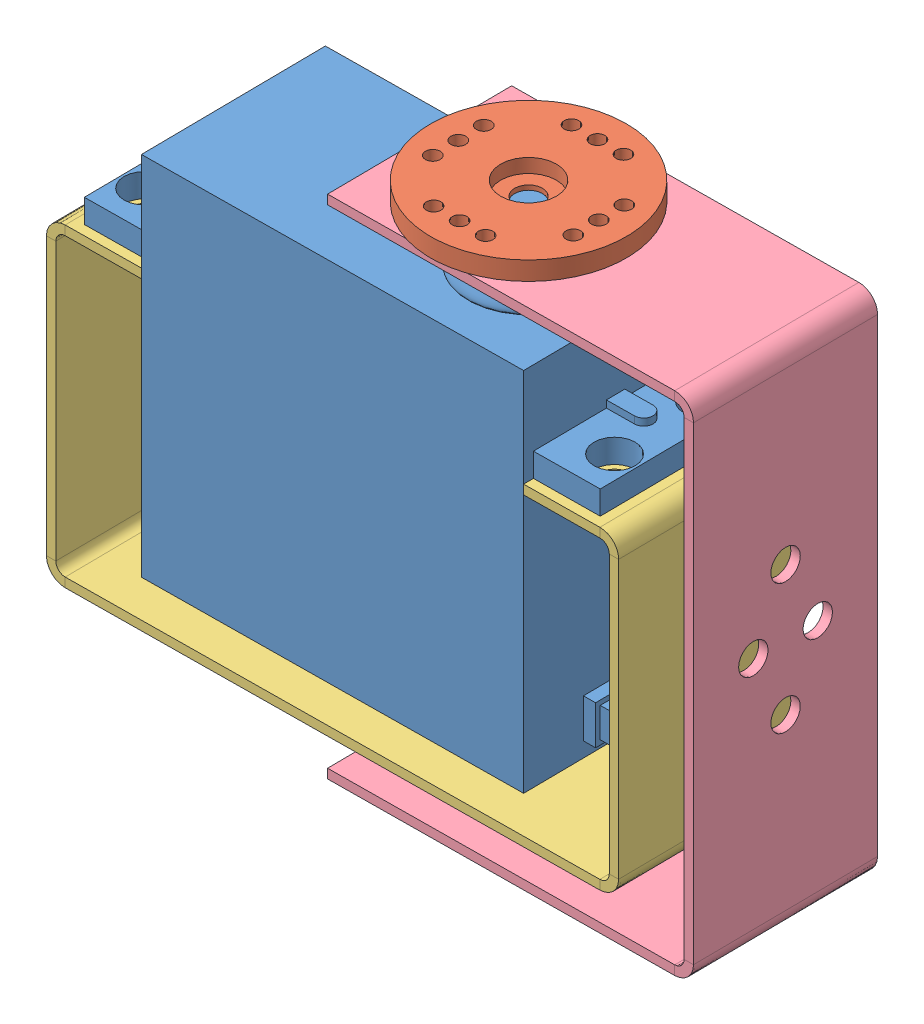
SolidWorks assembly servo_motor_bracket2, configuration ﾃﾞﾌｫﾙﾄ. Lengths in mm.
Overall size (69.14 56.5 21.25).
5 component instances, 5 part files, 8 mates.
Components (placement in the parent):
- servo_motor-1: servo_motor [ﾃﾞﾌｫﾙﾄ] at (-18.5258 -22.7875 66.8482) x (0.999945 0 -0.01047) z (0.01047 0 0.999945) size (54.94 45.5 20)
- servo_motor_soucer-1: servo_motor_soucer [ﾃﾞﾌｫﾙﾄ] at (12.7978 22.7125 56.5197) x (0.999953 0 -0.00966) z (0.00966 0 0.999953) size (21.05 5.7 21.05)
- servo_bracket2_base-2: servo_bracket2_base [ﾃﾞﾌｫﾙﾄ] at (-28.6452 -27.7875 66.9542) x (0.999945 0 -0.01047) z (0.01047 0 0.999945) size (60.94 33.81 20)
- servo_bracket2_cover-1: servo_bracket2_cover [ﾃﾞﾌｫﾙﾄ] at (39.2832 -31.7875 66.2643) x (0.999953 0 -0.00966) z (0.00966 0 0.999953) size (39 54.5 20)
- M3_spacer-1: M3_spacer [ﾃﾞﾌｫﾙﾄ] at (12.7978 -30.7875 56.5197) size (7 3 7)
Mates (geometry in assembly coordinates):
- 一致3: coincident anti-aligned: circle of servo_motor-1; circle of servo_motor_soucer-1
- 同心円3: concentric aligned: circle of servo_motor-1; circle of servo_bracket2_base-2
- 一致4: coincident anti-aligned: plane of servo_motor-1 through (29.2805 6.0225 65.2876) normal (0 -1 0); plane of servo_bracket2_base-2 through (-28.6452 6.0225 66.9542) normal (0 1 0)
- 同心円4: concentric aligned: circle of servo_motor_soucer-1; circle of servo_bracket2_cover-1
- 同心円5: concentric aligned: circle of servo_motor_soucer-1; circle of servo_bracket2_cover-1
- 一致6: coincident anti-aligned: plane of servo_motor_soucer-1 through (12.7978 22.7125 56.5197) normal (0 -1 0); plane of servo_bracket2_cover-1 through (40.2831 22.7125 66.2546) normal (0 1 0)
- 一致7: coincident anti-aligned: circle of servo_bracket2_base-2; circle of M3_spacer-1
- 同心円6: concentric aligned: circle of servo_motor-1; circle of servo_bracket2_base-2
